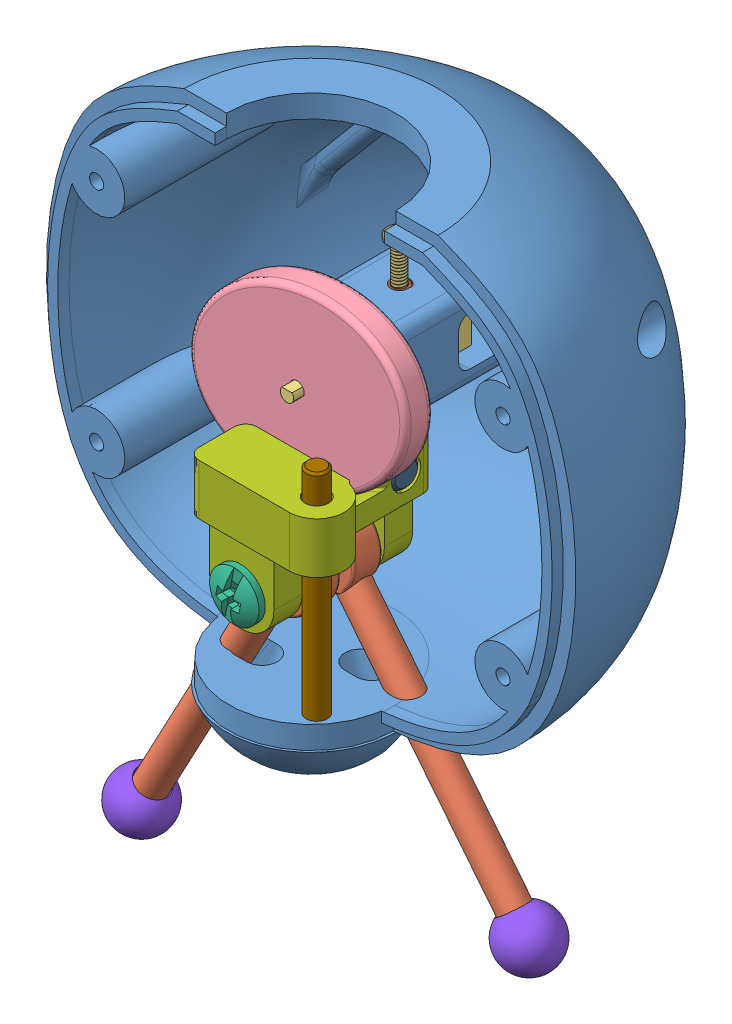
SolidWorks assembly head_back_assy, configuration Default. Lengths in mm.
Overall size (119.16 148.35 78.63).
16 component instances, 12 part files, 34 mates.
Components (placement in the parent):
- head_back-1: head_back [Default] at (-11.8247 82.6982 -6.2875) size (119.16 114.31 78.63)
- antenna_bottom-1: antenna_bottom [Default] at (-7.1516 0.8703 -10.9865) x (0.624558 -0.780979 0) z (0 0 -1) size (79.11 16.26 6.35)
- antenna_bottom-2: antenna_bottom [Default] at (-15.3499 0.114 -1.5885) x (-0.471145 -0.882056 0) z (0 0 -1) size (79.11 16.26 6.35)
- dc_motor-1: dc_motor [Default] at (-17.8572 45.0427 -36.3611) x (1 0 0) z (0 -1 0) size (12.06 35.51 10.03)
- crank-1: crank [Default] at (-11.8247 40.0262 -9.4625) x (0.420949 -0.907084 0) z (-0.907084 -0.420949 0) size (42.45 8.16 55.15)
- 98002A709_STEEL BINDING SCREWS-1: 98002A709_STEEL BINDING SCREWS [98002A709] at (-11.8247 6.7138 -14.225) x (0 0 -1) z (0 1 0) size (11.33 11.11 11.11)
- 99637A212_18-8 STAINLESS STEEL BINDING BARREL-1: 99637A212_18-8 STAINLESS STEEL BINDING BARREL [99637A212] at (-11.8247 6.7138 -28.5125) x (0 0 -1) z (-0.187402 -0.982283 0) size (35.2 11.11 11.11)
- antenna fixture-1: antenna fixture [Default] at (-11.8247 16.8738 -21.9085) x (-1 0 0) z (0 1 0) size (35.24 32.7 28.83)
- antenna_top-1: antenna_top [Default] at (32.5078 -48.7218 -10.9865) x (-0.139984 -0.111947 -0.983805) z (-0.624558 0.780979 0) size (12.7 12.7 11.69)
- antenna_top-2: antenna_top [Default] at (-45.2677 -55.8965 -1.5885) x (-0.735434 0.392828 -0.552108) z (0.471145 0.882056 0) size (12.7 12.7 11.69)
- 98381A325_DOWEL PIN-1: 98381A325_DOWEL PIN [98381A325] at (-0.3947 7.1332 3.8725) x (0 1 0) z (0.158679 0 0.98733) size (54.61 4.76 4.76)
- 98381A325_DOWEL PIN-2: 98381A325_DOWEL PIN [98381A325] at (-23.2547 7.1332 -16.4475) x (0 1 0) z (-0.401809 0 0.915724) size (54.61 4.76 4.76)
- 98381A539_ALLOY STEEL DOWEL PIN-1: 98381A539_ALLOY STEEL DOWEL PIN [98381A539] at (-15.3172 22.5888 3.5392) x (-1 0 0) z (0 -0.095607 0.995419) size (15.88 6.35 6.35)
- 98381A539_ALLOY STEEL DOWEL PIN-2: 98381A539_ALLOY STEEL DOWEL PIN [98381A539] at (-8.3322 22.5888 -16.2411) size (15.88 6.35 6.35)
- 93365A120_HEAT-SET INSERTS FOR PLASTICS-1: 93365A120_HEAT-SET INSERTS FOR PLASTICS [93365A120] at (-11.8247 49.0432 -26.1249) size (4.37 3.82 4.37)
- 91772A110_18-8 SS PAN HEAD PHILLIPS MACHINE SCREW-1: 91772A110_18-8 SS PAN HEAD PHILLIPS MACHINE SCREW [91772A110] at (-11.8247 45.0427 -26.1249) x (1 0 0) z (0 1 0) size (5.56 5.56 14.77)
Mates (geometry in assembly coordinates):
- Parallel15: parallel aligned: plane of head_back-1 through (-11.8247 82.6982 -6.2875) normal (0 1 0); plane of dc_motor-1 through (-17.8572 45.0427 -36.3611) normal (0 1 0)
- Concentric37: concentric aligned: cylinder of crank-1 through (-11.8247 40.0262 -3.1125) axis (0 0 -1) radius 1.6193; cylinder of dc_motor-1 through (-11.8247 40.0262 -0.8519) axis (0 0 -1) radius 1.4923
- Coincident56: coincident aligned: plane of head_back-1 through (-18.8097 32.5332 -10.8849) normal (0 0 1); plane of dc_motor-1 through (-17.8572 35.0097 -10.8849) normal (0 0 1)
- Coincident59: coincident: plane of head_back-1 through (-11.8247 82.6982 -6.2875) normal (1 0 0); point of dc_motor-1
- Coincident60: coincident anti-aligned: plane of 98002A709_STEEL BINDING SCREWS-1 through (-11.8247 6.7138 -22.1625) normal (0 0 1); plane of 99637A212_18-8 STAINLESS STEEL BINDING BARREL-1 through (-11.8247 6.7138 -22.1625) normal (0 0 -1)
- Concentric39: concentric anti-aligned: circle of 98002A709_STEEL BINDING SCREWS-1; circle of 99637A212_18-8 STAINLESS STEEL BINDING BARREL-1
- Concentric40: concentric anti-aligned: cylinder of antenna_bottom-1 through (-11.8247 6.7138 -14.1615) axis (0 0 1) radius 4.0958; cylinder of 99637A212_18-8 STAINLESS STEEL BINDING BARREL-1 through (-11.8247 6.7138 -12.6375) axis (0 0 -1) radius 3.175
- Concentric41: concentric anti-aligned: cylinder of antenna_bottom-2 through (-11.8247 6.7138 -4.7635) axis (0 0 1) radius 4.0958; cylinder of 99637A212_18-8 STAINLESS STEEL BINDING BARREL-1 through (-11.8247 6.7138 -12.6375) axis (0 0 -1) radius 3.175
- Distance2: distance = 3.048 mm anti-aligned: plane of antenna_bottom-1 through (-11.8247 6.7138 -7.8115) normal (0 0 1); plane of antenna_bottom-2 through (-11.8247 6.7138 -4.7635) normal (0 0 -1)
- Distance3: distance = 0.254 mm anti-aligned: plane of 99637A212_18-8 STAINLESS STEEL BINDING BARREL-1 through (-11.8247 6.7138 9.5875) normal (0 0 -1); plane of antenna fixture-1 through (-11.8247 6.7138 9.3335) normal (0 0 1)
- Distance4: distance = 1.397 mm anti-aligned: plane of antenna fixture-1 through (-11.8247 6.7138 2.9835) normal (0 0 -1); plane of antenna_bottom-2 through (-11.8247 6.7138 1.5865) normal (0 0 1)
- Concentric43: concentric anti-aligned: cylinder of 99637A212_18-8 STAINLESS STEEL BINDING BARREL-1 through (-11.8247 6.7138 -12.6375) axis (0 0 -1) radius 3.175; cylinder of antenna fixture-1 through (-11.8247 6.7138 2.9835) axis (0 0 1) radius 3.429
- Coincident69: coincident anti-aligned: plane of dc_motor-1 through (-11.8247 40.0262 -9.4625) normal (0 0 1); plane of crank-1 through (-11.8247 40.0262 -9.4625) normal (0 0 -1)
- Coincident71: coincident anti-aligned: plane of antenna_bottom-1 through (32.5078 -48.7218 -7.8115) normal (0.624558 -0.780979 0); plane of antenna_top-1 through (32.5078 -48.7218 -10.9865) normal (-0.624558 0.780979 0)
- Coincident72: coincident anti-aligned: plane of antenna_bottom-2 through (-45.2677 -55.8965 1.5865) normal (-0.471145 -0.882056 0); plane of antenna_top-2 through (-45.2677 -55.8965 -1.5885) normal (0.471145 0.882056 0)
- Concentric46: concentric aligned: cylinder of antenna_bottom-2 through (-15.3499 0.114 -1.5885) axis (0.471145 0.882056 0) radius 3.175; cylinder of antenna_top-2 through (-45.2677 -55.8965 -1.5885) axis (0.471145 0.882056 0) radius 3.429
- Concentric47: concentric aligned: cylinder of antenna_bottom-1 through (-7.1516 0.8703 -10.9865) axis (-0.624558 0.780979 0) radius 3.175; cylinder of antenna_top-1 through (32.5078 -48.7218 -10.9865) axis (-0.624558 0.780979 0) radius 3.429
- Concentric48: concentric aligned: cylinder of head_back-1 through (-0.3947 -20.1718 3.8725) axis (0 1 0) radius 2.3813; cylinder of 98381A325_DOWEL PIN-1 through (-0.3947 -20.1718 3.8725) axis (0 1 0) radius 2.3813
- Concentric49: concentric aligned: cylinder of head_back-1 through (-23.2547 -20.1718 -16.4475) axis (0 1 0) radius 2.3813; cylinder of 98381A325_DOWEL PIN-2 through (-23.2547 -20.1718 -16.4475) axis (0 1 0) radius 2.3813
- Coincident73: coincident anti-aligned: plane of head_back-1 through (-0.3947 -20.1718 3.8725) normal (0 1 0); plane of 98381A325_DOWEL PIN-1 through (-0.3947 -20.1718 3.8725) normal (0 -1 0)
- Coincident74: coincident anti-aligned: plane of head_back-1 through (-23.2547 -20.1718 -16.4475) normal (0 1 0); plane of 98381A325_DOWEL PIN-2 through (-23.2547 -20.1718 -16.4475) normal (0 -1 0)
- Concentric50: concentric anti-aligned: cylinder of antenna fixture-1 through (-23.2547 28.3038 -16.4475) axis (0 -1 0) radius 2.6353; cylinder of 98381A325_DOWEL PIN-2 through (-23.2547 -20.1718 -16.4475) axis (0 1 0) radius 2.3813
- Concentric51: concentric anti-aligned: cylinder of antenna fixture-1 through (-0.3947 28.3038 3.8725) axis (0 -1 0) radius 2.6353; cylinder of 98381A325_DOWEL PIN-1 through (-0.3947 -20.1718 3.8725) axis (0 1 0) radius 2.3813
- Concentric52: concentric aligned: cylinder of antenna fixture-1 through (-7.3797 22.5888 3.5392) axis (-1 0 0) radius 3.302; cylinder of 98381A539_ALLOY STEEL DOWEL PIN-1 through (-7.3797 22.5888 3.5392) axis (-1 0 0) radius 3.175
- Concentric53: concentric aligned: cylinder of antenna fixture-1 through (-16.2697 22.5888 -16.2411) axis (1 0 0) radius 3.302; cylinder of 98381A539_ALLOY STEEL DOWEL PIN-2 through (-16.2697 22.5888 -16.2411) axis (1 0 0) radius 3.175
- Coincident75: coincident anti-aligned: plane of antenna fixture-1 through (-16.2697 22.5888 -16.2411) normal (1 0 0); plane of 98381A539_ALLOY STEEL DOWEL PIN-2 through (-16.2697 22.5888 -16.2411) normal (-1 0 0)
- Coincident76: coincident anti-aligned: plane of antenna fixture-1 through (-7.3797 22.5888 3.5392) normal (-1 0 0); plane of 98381A539_ALLOY STEEL DOWEL PIN-1 through (-7.3797 22.5888 3.5392) normal (1 0 0)
- Tangent2: tangent: circle of head_back_6-1; cylinder of antenna_bottom-1 through (-7.1516 0.8703 -10.9865) axis (-0.624558 0.780979 0) radius 3.175
- Concentric54: concentric anti-aligned: circle of head_back_6-1; circle of 93365A120_HEAT-SET INSERTS FOR PLASTICS-1
- Coincident77: coincident aligned: plane of head_back-1 through (-18.8097 49.0432 -65.8665) normal (0 1 0); plane of 93365A120_HEAT-SET INSERTS FOR PLASTICS-1 through (-11.8247 49.0432 -26.1249) normal (0 1 0)
- Coincident78: coincident anti-aligned: plane of dc_motor-1 through (-17.8572 45.0427 -36.3611) normal (0 1 0); plane of 91772A110_18-8 SS PAN HEAD PHILLIPS MACHINE SCREW-1 through (-11.8247 45.0427 -26.1249) normal (0 -1 0)
- Concentric55: concentric anti-aligned: circle of 93365A120_HEAT-SET INSERTS FOR PLASTICS-1; circle of 91772A110_18-8 SS PAN HEAD PHILLIPS MACHINE SCREW-1
- Coincident81: coincident anti-aligned: plane of head_back-1 through (-18.1112 45.0427 -65.8665) normal (0 -1 0); plane of dc_motor-1 through (-17.8572 45.0427 -36.3611) normal (0 1 0)
- LimitDistance2: limit distance = 1.6895 mm anti-aligned: plane of head_back-1 through (-18.8097 29.9932 -65.8665) normal (0 -1 0); plane of antenna fixture-1 through (-20.7147 28.3038 7.5238) normal (0 1 0)
